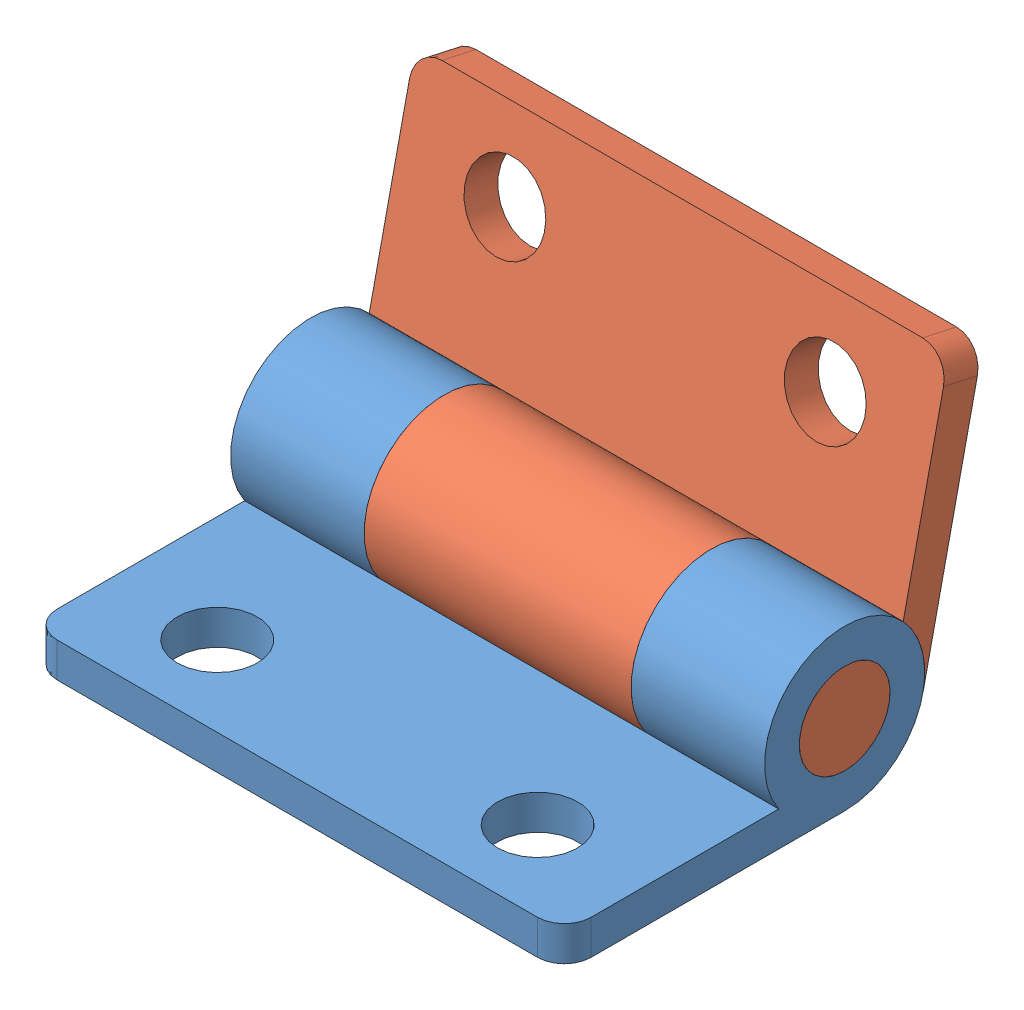
SolidWorks assembly 003-合页, configuration 合页. Lengths in mm.
Overall size (20 14.47 15.69).
2 component instances, 2 part files, 2 mates.
Components (placement in the parent):
- 003-合页01-1: 003-合页01 [合页01] at (-27.0142 -0.6853 26.75) size (20 6 13.5)
- 003-合页02-1: 003-合页02 [合页02] at (-17.0142 1.6698 13.3201) x (1 0 0) z (0 -0.976623 0.21496) size (20 6 13.5)
Mates (geometry in assembly coordinates):
- 同心1: concentric anti-aligned: cylinder of 003-合页01-1 through (-12.0142 2.3147 16.25) axis (1 0 0) radius 1.7; cylinder of 003-合页02-1 through (-7.0142 2.3147 16.25) axis (-1 0 0) radius 1.7
- 重合1: coincident aligned: plane of 003-合页01-1 through (-7.0142 -0.6853 26.75) normal (1 0 0); plane of 003-合页02-1 through (-7.0142 2.3147 16.25) normal (1 0 0)
